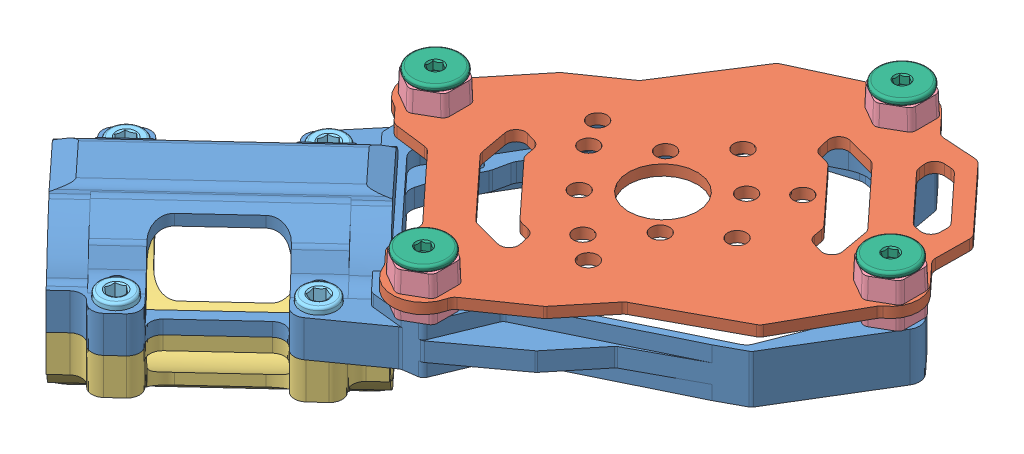
SolidWorks assembly SupportoMotore, configuration Default. Lengths in mm.
Overall size (71.65 19.18 69.8).
15 component instances, 6 part files, 30 mates.
Components (placement in the parent):
- Êðîíøòåéí TL96029-1: Êðîíøòåéí TL96029 [Default] at (-6.7932 0 20.5763) x (0.733531 0 -0.679656) z (0.679656 0 0.733531) size (64 9.09 32.91)
- Ïëàñòèíà îïîðíàÿ TL96029-1: Ïëàñòèíà îïîðíàÿ TL96029 [Default] at (27.504 7.829 -11.202) x (0.733531 0 -0.679656) z (0.679656 0 0.733531) size (42.88 1.09 32.88)
- Ïðèæèì TL96029-1: Ïðèæèì TL96029 [Default] at (1.3333 4.7009 13.0466) x (0.733531 0 -0.679656) z (-0.679656 0 -0.733531) size (24.96 9.09 23.49)
- Äåìïôåð TL96029-1: Äåìïôåð TL96029 [Default] at (20.0865 5.5668 11.1575) x (0.866025 0 0.5) z (-0.5 0 0.866025) size (5.56 4.48 4.99)
- Äåìïôåð TL96029-2: Äåìïôåð TL96029 [Default] at (4.6447 5.5668 -5.5083) x (0.866025 0 0.5) z (-0.5 0 0.866025) size (5.56 4.48 4.99)
- Äåìïôåð TL96029-3: Äåìïôåð TL96029 [Default] at (44.6392 5.5668 -12.2462) x (0.866025 0 0.5) z (-0.5 0 0.866025) size (5.56 4.48 4.99)
- Äåìïôåð TL96029-4: Äåìïôåð TL96029 [Default] at (29.8498 5.5668 -28.2079) x (0.866025 0 0.5) z (-0.5 0 0.866025) size (5.56 4.48 4.99)
- DIN_912 M3_10 black-1: DIN_912 M3_10 black [Default] at (-142.6613 -62.2884 12.3804) x (0 1 0) z (0.934845 0 0.355055) size (8.36 3.52 3.52)
- DIN_912 M3_10 black-2: DIN_912 M3_10 black [Default] at (-129.6841 -62.2884 111.6768) x (0 1 0) z (0.937251 0 -0.348656) size (8.36 3.52 3.52)
- DIN_912 M3_10 black-3: DIN_912 M3_10 black [Default] at (-116.6347 -62.2884 125.7606) x (0 1 0) z (0.937251 0 -0.348656) size (8.36 3.52 3.52)
- DIN_912 M3_10 black-4: DIN_912 M3_10 black [Default] at (-118.8865 -62.2884 101.6722) x (0 1 0) z (0.937251 0 -0.348656) size (8.36 3.52 3.52)
- Âèíò Ì3õ10 ñ ïëîñêîé ãîëîâêîé ïîä øåñòèãðàííèê-1: Âèíò Ì3õ10 ñ ïëîñêîé ãîëîâêîé ïîä øåñòèãðàííèê [Default] at (20.0865 13.4036 11.1575) x (0.01124 0 -0.999937) z (-0.999937 0 -0.01124) size (5.06 7.05 5.06)
- Âèíò Ì3õ10 ñ ïëîñêîé ãîëîâêîé ïîä øåñòèãðàííèê-2: Âèíò Ì3õ10 ñ ïëîñêîé ãîëîâêîé ïîä øåñòèãðàííèê [Default] at (44.6392 13.4036 -12.2462) x (0.01124 0 -0.999937) z (-0.999937 0 -0.01124) size (5.06 7.05 5.06)
- Âèíò Ì3õ10 ñ ïëîñêîé ãîëîâêîé ïîä øåñòèãðàííèê-3: Âèíò Ì3õ10 ñ ïëîñêîé ãîëîâêîé ïîä øåñòèãðàííèê [Default] at (29.8498 13.4036 -28.2079) x (0.01124 0 -0.999937) z (-0.999937 0 -0.01124) size (5.06 7.05 5.06)
- Âèíò Ì3õ10 ñ ïëîñêîé ãîëîâêîé ïîä øåñòèãðàííèê-4: Âèíò Ì3õ10 ñ ïëîñêîé ãîëîâêîé ïîä øåñòèãðàííèê [Default] at (4.6447 13.4036 -5.5083) x (0.01124 0 -0.999937) z (-0.999937 0 -0.01124) size (5.06 7.05 5.06)
Mates (geometry in assembly coordinates):
- Concentrico1: concentric anti-aligned: cylinder of Êðîíøòåéí TL96029-1 through (0.2074 5.639 1.0025) axis (0 1 0) radius 0.896; cylinder of DIN_912 M3_10 black-4 through (0.2074 -2.041 1.0025) axis (0 -1 0) radius 0.96
- Concentrico2: concentric anti-aligned: cylinder of Êðîíøòåéí TL96029-1 through (-10.5902 5.639 11.007) axis (0 1 0) radius 0.896; cylinder of DIN_912 M3_10 black-2 through (-10.5902 -2.041 11.007) axis (0 -1 0) radius 0.96
- Concentrico3: concentric anti-aligned: cylinder of Êðîíøòåéí TL96029-1 through (2.4592 5.639 25.0908) axis (0 1 0) radius 1.792; cylinder of DIN_912 M3_10 black-3 through (2.4592 -2.041 25.0908) axis (0 -1 0) radius 0.96
- Concentrico4: concentric anti-aligned: cylinder of Êðîíøòåéí TL96029-1 through (13.2568 5.639 15.0863) axis (0 1 0) radius 0.896; cylinder of DIN_912 M3_10 black-1 through (13.2568 -2.041 15.0863) axis (0 -1 0) radius 0.96
- Coincidente1: coincident anti-aligned: plane of Êðîíøòåéí TL96029-1 through (3.1165 4.359 24.4818) normal (0 1 0); plane of DIN_912 M3_10 black-3 through (4.1088 4.359 24.4772) normal (0 -1 0)
- Coincidente2: coincident anti-aligned: plane of Êðîíøòåéí TL96029-1 through (13.914 4.359 14.4773) normal (0 1 0); plane of DIN_912 M3_10 black-1 through (14.9021 4.359 15.7111) normal (0 -1 0)
- Coincidente3: coincident anti-aligned: plane of Êðîíøòåéí TL96029-1 through (0.8646 4.359 0.3935) normal (0 1 0); circle of DIN_912 M3_10 black-4
- Coincidente4: coincident anti-aligned: plane of Êðîíøòåéí TL96029-1 through (-9.9329 4.359 10.398) normal (0 1 0); plane of DIN_912 M3_10 black-2 through (-8.9406 4.359 10.3934) normal (0 -1 0)
- Concentrico6: concentric anti-aligned: cylinder of Ïðèæèì TL96029-1 through (0.2074 1.895 1.0025) axis (0 1 0) radius 0.8; cylinder of DIN_912 M3_10 black-4 through (0.2074 -2.041 1.0025) axis (0 -1 0) radius 0.96
- Concentrico7: concentric anti-aligned: cylinder of Ïðèæèì TL96029-1 through (2.4592 1.895 25.0908) axis (0 1 0) radius 0.8; cylinder of DIN_912 M3_10 black-3 through (2.4592 -2.041 25.0908) axis (0 -1 0) radius 0.96
- Coincidente5: coincident anti-aligned: plane of Êðîíøòåéí TL96029-1 through (1.3333 1.895 13.0466) normal (0 -1 0); plane of Ïðèæèì TL96029-1 through (1.3333 1.895 13.0466) normal (0 1 0)
- Concentrico8: concentric anti-aligned: cylinder of Êðîíøòåéí TL96029-1 through (20.0865 6.855 11.1575) axis (0 1 0) radius 0.8; cylinder of Âèíò Ì3õ10 ñ ïëîñêîé ãîëîâêîé ïîä øåñòèãðàííèê-1 through (20.0865 4.935 11.1575) axis (0 -1 0) radius 0.96
- Concentrico9: concentric aligned: cylinder of Äåìïôåð TL96029-1 through (20.0865 6.855 11.1575) axis (0 -1 0) radius 1.12; cylinder of Âèíò Ì3õ10 ñ ïëîñêîé ãîëîâêîé ïîä øåñòèãðàííèê-1 through (20.0865 4.935 11.1575) axis (0 -1 0) radius 1.12
- Concentrico10: concentric aligned: circle of Êðîíøòåéí TL96029-1; circle of Âèíò Ì3õ10 ñ ïëîñêîé ãîëîâêîé ïîä øåñòèãðàííèê-4
- Coincidente6: coincident aligned: circle of Äåìïôåð TL96029-2; cylinder of Âèíò Ì3õ10 ñ ïëîñêîé ãîëîâêîé ïîä øåñòèãðàííèê-4 through (4.6447 4.935 -5.5083) axis (0 -1 0) radius 1.12
- Concentrico11: concentric aligned: cylinder of Äåìïôåð TL96029-4 through (29.8498 6.855 -28.2079) axis (0 -1 0) radius 1.92; cylinder of Âèíò Ì3õ10 ñ ïëîñêîé ãîëîâêîé ïîä øåñòèãðàííèê-3 through (29.8498 4.935 -28.2079) axis (0 -1 0) radius 0.96
- Concentrico12: concentric aligned: cylinder of Äåìïôåð TL96029-3 through (44.6392 6.855 -12.2462) axis (0 -1 0) radius 1.92; cylinder of Âèíò Ì3õ10 ñ ïëîñêîé ãîëîâêîé ïîä øåñòèãðàííèê-2 through (44.6392 4.935 -12.2462) axis (0 -1 0) radius 0.96
- Coincidente7: coincident anti-aligned: plane of Äåìïôåð TL96029-4 through (30.8198 11.335 -27.6479) normal (0 1 0); plane of Âèíò Ì3õ10 ñ ïëîñêîé ãîëîâêîé ïîä øåñòèãðàííèê-3 through (29.8214 11.335 -25.68) normal (0 -1 0)
- Coincidente9: coincident anti-aligned: plane of Äåìïôåð TL96029-3 through (45.6091 11.335 -11.6862) normal (0 1 0); plane of Âèíò Ì3õ10 ñ ïëîñêîé ãîëîâêîé ïîä øåñòèãðàííèê-2 through (44.6107 11.335 -9.7184) normal (0 -1 0)
- Coincidente10: coincident anti-aligned: plane of Äåìïôåð TL96029-1 through (21.0565 11.335 11.7175) normal (0 1 0); plane of Âèíò Ì3õ10 ñ ïëîñêîé ãîëîâêîé ïîä øåñòèãðàííèê-1 through (20.0581 11.335 13.6853) normal (0 -1 0)
- Coincidente11: coincident anti-aligned: plane of Äåìïôåð TL96029-2 through (5.6147 11.335 -4.9483) normal (0 1 0); plane of Âèíò Ì3õ10 ñ ïëîñêîé ãîëîâêîé ïîä øåñòèãðàííèê-4 through (4.6163 11.335 -2.9805) normal (0 -1 0)
- Concentrico14: concentric anti-aligned: cylinder of Ïëàñòèíà îïîðíàÿ TL96029-1 through (29.8498 9.223 -28.2079) axis (0 -1 0) radius 1.92; circle of Âèíò Ì3õ10 ñ ïëîñêîé ãîëîâêîé ïîä øåñòèãðàííèê-3
- Concentrico15: concentric aligned: cylinder of Ïëàñòèíà îïîðíàÿ TL96029-1 through (44.6392 9.223 -12.2462) axis (0 -1 0) radius 1.92; cylinder of Äåìïôåð TL96029-3 through (44.6392 6.855 -12.2462) axis (0 -1 0) radius 1.92
- Concentrico16: concentric aligned: cylinder of Ïëàñòèíà îïîðíàÿ TL96029-1 through (20.0865 9.223 11.1575) axis (0 -1 0) radius 1.92; cylinder of Äåìïôåð TL96029-1 through (20.0865 6.855 11.1575) axis (0 -1 0) radius 1.92
- Concentrico17: concentric anti-aligned: cylinder of Ïëàñòèíà îïîðíàÿ TL96029-1 through (4.6447 9.223 -5.5083) axis (0 -1 0) radius 1.92; circle of Âèíò Ì3õ10 ñ ïëîñêîé ãîëîâêîé ïîä øåñòèãðàííèê-4
- Coincidente12: coincident anti-aligned: plane of Êðîíøòåéí TL96029-1 through (30.0189 6.855 -29.6312) normal (0 1 0); plane of Äåìïôåð TL96029-1 through (22.8578 6.855 12.7575) normal (0 -1 0)
- Coincidente13: coincident anti-aligned: plane of Ïëàñòèíà îïîðíàÿ TL96029-1 through (4.6447 9.223 -5.5083) normal (0 1 0); plane of Äåìïôåð TL96029-1 through (21.7493 9.223 12.1175) normal (0 -1 0)
- Coincidente14: coincident aligned: plane of Âèíò Ì3õ10 ñ ïëîñêîé ãîëîâêîé ïîä øåñòèãðàííèê-1 through (20.0793 11.975 11.7975) normal (0 1 0); plane of Âèíò Ì3õ10 ñ ïëîñêîé ãîëîâêîé ïîä øåñòèãðàííèê-4 through (4.6375 11.975 -4.8684) normal (0 1 0)
- Coincidente15: coincident aligned: plane of Âèíò Ì3õ10 ñ ïëîñêîé ãîëîâêîé ïîä øåñòèãðàííèê-1 through (20.0793 11.975 11.7975) normal (0 1 0); plane of Âèíò Ì3õ10 ñ ïëîñêîé ãîëîâêîé ïîä øåñòèãðàííèê-2 through (44.632 11.975 -11.6063) normal (0 1 0)
- Coincidente16: coincident aligned: plane of Âèíò Ì3õ10 ñ ïëîñêîé ãîëîâêîé ïîä øåñòèãðàííèê-1 through (20.0793 11.975 11.7975) normal (0 1 0); plane of Âèíò Ì3õ10 ñ ïëîñêîé ãîëîâêîé ïîä øåñòèãðàííèê-3 through (29.8426 11.975 -27.5679) normal (0 1 0)
